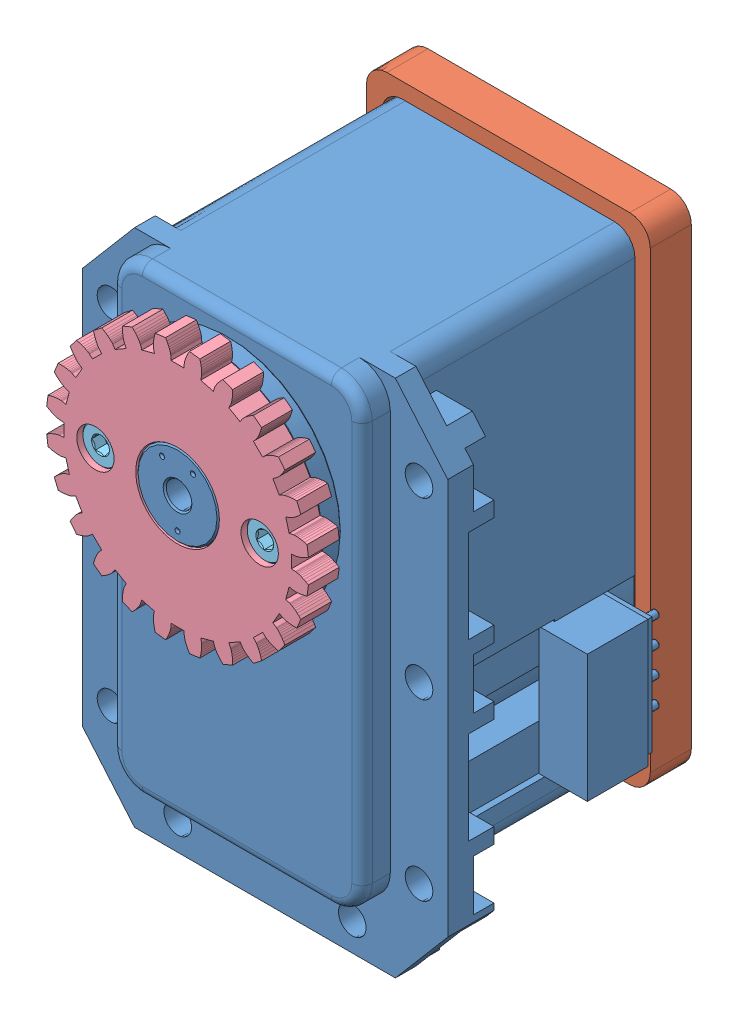
SolidWorks assembly block_actuator_gear_o, configuration Default. Lengths in mm.
Overall size (35.6 56.79 39.77).
9 component instances, 5 part files, 18 mates.
Components (placement in the parent):
- dynamixel MX-28-exposed-1: dynamixel MX-28-exposed [Back Off] at origin size (35.6 50.6 39.77)
- d2_o-1: d2_o [Default] at (-12.375 -33.125 -8.75) x (0 1 0) z (0 0 -1) size (48.25 27.65 4)
- 91772A266 2-56 L5-4 pan-1: 91772A266 2-56 L5-4 pan [91772A266] at (-9.3 9 12.65) x (-0.205276 0.978704 0) z (0 0 -1) size (4.24 4.24 27.06)
- 91772A266 2-56 L5-4 pan-2: 91772A266 2-56 L5-4 pan [91772A266] at (9.2 9 12.65) x (-0.795891 0.60544 0) z (0 0 -1) size (4.24 4.24 27.06)
- 91772A266 2-56 L5-4 pan-3: 91772A266 2-56 L5-4 pan [91772A266] at (9.2 -30 12.65) x (-0.25415 0.967165 0) z (0 0 -1) size (4.24 4.24 27.06)
- 91772A266 2-56 L5-4 pan-4: 91772A266 2-56 L5-4 pan [91772A266] at (-9.3 -30 12.65) x (-0.098208 -0.995166 0) z (0 0 -1) size (4.24 4.24 27.06)
- b2_o-1: b2_o [Default] at (0 0 20.52) size (25.49 55.91 3)
- 91292A003 M2 L3 socket-1: 91292A003 M2 L3 socket [91292A003] at (-8 0 18.02) x (-0.923728 -0.383049 0) z (0 0 -1) size (3.8 3.8 5.09)
- 91292A003 M2 L3 socket-2: 91292A003 M2 L3 socket [91292A003] at (8 0 18.02) x (-0.577343 -0.816502 0) z (0 0 -1) size (3.8 3.8 5.09)
Mates (geometry in assembly coordinates):
- Concentric2: concentric anti-aligned: cylinder of dynamixel MX-28-exposed-1 through (9.2 9 1.25) axis (0 0 -1) radius 1.15; cylinder of d2_o-1 through (9.2 9 -13.1906) axis (0 0 1) radius 1.075
- Parallel1: parallel aligned: plane of dynamixel MX-28-exposed-1 through (12.2 12 -17.75) normal (0 1 0); plane of d2_o-1 through (-13.875 13.625 -12.75) normal (0 1 0)
- Coincident2: coincident anti-aligned: plane of dynamixel MX-28-exposed-1 through (-10.2 -31 -8.75) normal (0 0 -1); plane of d2_o-1 through (-12.375 -33.125 -8.75) normal (0 0 1)
- Concentric4: concentric anti-aligned: cylinder of d2_o-1 through (-9.3 9 -13.1906) axis (0 0 1) radius 1.075; circle of 91772A266 2-56 L5-4 pan-1
- Coincident3: coincident anti-aligned: plane of d2_o-1 through (-12.375 -33.125 -12.75) normal (0 0 -1); plane of 91772A266 2-56 L5-4 pan-1 through (-9.3 9 -12.75) normal (0 0 1)
- Concentric5: concentric anti-aligned: cylinder of d2_o-1 through (9.2 9 -13.1906) axis (0 0 1) radius 1.075; circle of 91772A266 2-56 L5-4 pan-2
- Coincident4: coincident anti-aligned: plane of d2_o-1 through (-12.375 -33.125 -12.75) normal (0 0 -1); plane of 91772A266 2-56 L5-4 pan-2 through (9.2 9 -12.75) normal (0 0 1)
- Concentric6: concentric anti-aligned: cylinder of d2_o-1 through (9.2 -30 -13.1906) axis (0 0 1) radius 1.075; circle of 91772A266 2-56 L5-4 pan-3
- Coincident5: coincident aligned: plane of d2_o-1 through (-12.375 -33.125 -12.75) normal (0 0 -1); circle of 91772A266 2-56 L5-4 pan-3
- Concentric7: concentric anti-aligned: cylinder of d2_o-1 through (-9.3 -30 -13.1906) axis (0 0 1) radius 1.075; circle of 91772A266 2-56 L5-4 pan-4
- Coincident6: coincident anti-aligned: plane of d2_o-1 through (-12.375 -33.125 -12.75) normal (0 0 -1); plane of 91772A266 2-56 L5-4 pan-4 through (-9.3 -30 -12.75) normal (0 0 1)
- Concentric13: concentric anti-aligned: cylinder of dynamixel MX-28-exposed-1 through (0 0 37.8337) axis (0 0 -1) radius 4; cylinder of b2_o-1 through (0 0 20.52) axis (0 0 1) radius 4.075
- Coincident11: coincident anti-aligned: plane of dynamixel MX-28-exposed-1 through (0 0 20.52) normal (0 0 1); plane of b2_o-1 through (0 0 20.52) normal (0 0 -1)
- Concentric14: concentric aligned: cylinder of dynamixel MX-28-exposed-1 through (-8 0 -19.251) axis (0 0 1) radius 0.9; cylinder of b2_o-1 through (-8 0 21.02) axis (0 0 1) radius 1.825
- Concentric15: concentric anti-aligned: cylinder of b2_o-1 through (-8 0 21.02) axis (0 0 1) radius 1.825; cylinder of 91292A003 M2 L3 socket-1 through (-8 0 23.02) axis (0 0 -1) radius 1.9
- Coincident12: coincident anti-aligned: plane of b2_o-1 through (-8 0 21.02) normal (0 0 1); plane of 91292A003 M2 L3 socket-1 through (-8 0 21.02) normal (0 0 -1)
- Concentric16: concentric anti-aligned: cylinder of b2_o-1 through (8 0 21.02) axis (0 0 1) radius 1.825; cylinder of 91292A003 M2 L3 socket-2 through (8 0 23.02) axis (0 0 -1) radius 1.9
- Coincident13: coincident anti-aligned: plane of b2_o-1 through (8 0 21.02) normal (0 0 1); plane of 91292A003 M2 L3 socket-2 through (8 0 21.02) normal (0 0 -1)
